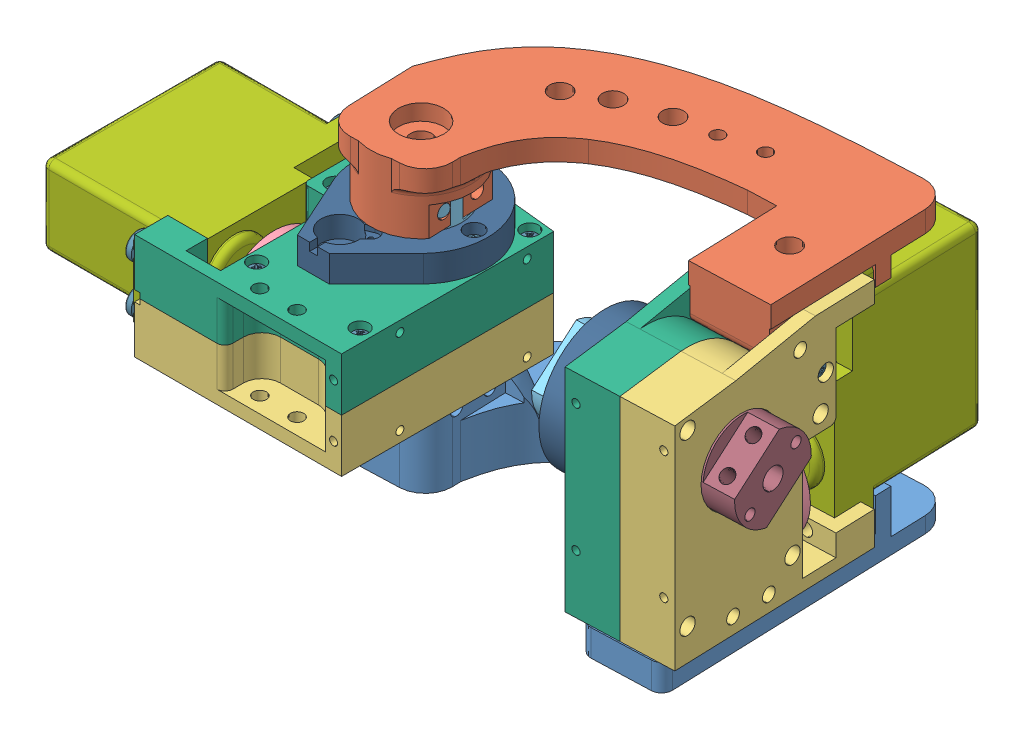
SolidWorks assembly Mirrorshoulder assm, configuration Default. Lengths in mm.
Overall size (244.05 136 145.04).
60 component instances, 14 part files, 11 mates.
Components (placement in the parent):
- bottom bracket-1: bottom bracket [Default] at (151.0032 -30.5 42.744) x (0.999397 0 -0.034735) z (0 1 0) size (146.28 120.67 30)
- top bracket L-1: top bracket L [Default] at (226.2586 75.5 40.1284) x (-0.999397 0 0.034735) z (0 -1 0) size (146.28 120.67 55)
- large gearbox mirror-1: large gearbox mirror [Default] at (-3.3718 24.2748 38.5998) x (0 0 1) z (-1 0 0) size (90.22 74 134.56)
  - bottom housing mirror-1: bottom housing mirror [Default] at (7.4002 -24.2748 -89.7718) x (1 0 0) z (0 -1 0) size (87.5 78 20)
  - wormscrew-1: wormscrew [Default] at (21.4002 -4.2748 -75.7718) x (-0.47589 -0.879505 0) z (0 0 -1) size (40 40 51)
  - driveshaft cog-1: driveshaft cog [Default] at (-6.5998 -9.2748 -103.2718) x (0.623441 0 -0.78187) z (0 1 0) size (49.29 49.31 47)
  - top housing mirror-1: top housing mirror [Default] at (-6.5998 15.7252 -103.2718) x (-1 0 0) z (0 1 0) size (87.5 78 40)
  - HS-805BB-1: HS-805BB [Default] at (2.9002 -19.2748 -28.6693) x (1 0 0) z (0 1 0) size (83 68.8 30)
  - 608ZZ-1: 608ZZ [Default] at (21.4002 -4.2748 -127.5718) x (0.996867 0.079098 0) z (0 0 1) size (22 22 7)
  - 6806 30x42x7-1: 6806 30x42x7 [Default] at (-6.5998 -22.2748 -103.2718) x (0.979879 0 -0.199591) z (0 1 0) size (42 42 7)
  - 6806 30x42x7-2: 6806 30x42x7 [Default] at (-6.5998 9.7252 -103.2718) x (0.968497 0 -0.249026) z (0 -1 0) size (42 42 7)
  - pot holder mirror-1: pot holder mirror [Default] at (-6.5998 15.7252 -103.2718) x (0 0 1) z (0 -1 0) size (50 60 10)
  - cog brace-1: cog brace [Default] at (18.6002 9.7252 -104.6718) x (1 0 0) z (0 -1 0) size (8.5 22.65 3)
  - pot cog-1: pot cog [Default] at (18.6002 12.7252 -97.7718) x (0.51355 0 -0.85806) z (0 -1 0) size (28 27.88 7.9)
  - driveshaft-1: driveshaft [Default] at (-6.5998 -9.2748 -103.2718) x (-0.623441 0 0.78187) z (0 -1 0) size (36.44 35.48 27)
  - Pan Head Cross Recess Screw_ISO-1: Pan Head Cross Recess Screw_ISO [ISO 7045 - M3 x 10 - Z --- 10N] at (-26.5998 23.1252 -103.2718) x (0 -1 0) z (0 0 -1) size (12.35 5.6 5.6)
  - Pan Head Cross Recess Screw_ISO-2: Pan Head Cross Recess Screw_ISO [ISO 7045 - M3 x 10 - Z --- 10N] at (-6.5998 23.1252 -123.2718) x (0 -1 0) z (0.495758 0 -0.868461) size (12.35 5.6 5.6)
  - Pan Head Cross Recess Screw_ISO-3: Pan Head Cross Recess Screw_ISO [ISO 7045 - M3 x 10 - Z --- 10N] at (-6.5998 23.1252 -83.2718) x (0 -1 0) z (0.927545 0 -0.373711) size (12.35 5.6 5.6)
  - Pan Head Cross Recess Screw_ISO-4: Pan Head Cross Recess Screw_ISO [ISO 7045 - M5 x 12 - Z --- 12N] at (-34.5998 -13.2748 -42.0718) x (0 0 -1) z (-1 0 0) size (15.63 9.5 9.5)
  - Pan Head Cross Recess Screw_ISO-5: Pan Head Cross Recess Screw_ISO [ISO 7045 - M5 x 12 - Z --- 12N] at (-34.5998 4.7252 -42.0718) x (0 0 -1) z (-1 0 0) size (15.63 9.5 9.5)
  - Pan Head Cross Recess Screw_ISO-6: Pan Head Cross Recess Screw_ISO [ISO 7045 - M3 x 30 - Z --- 25N] at (-27.0895 14.1252 -123.7718) x (0 -1 0) z (0 0 -1) size (32.35 5.6 5.6)
  - Pan Head Cross Recess Screw_ISO-7: Pan Head Cross Recess Screw_ISO [ISO 7045 - M3 x 30 - Z --- 25N] at (-18.0998 -22.6748 -69.7718) x (0 1 0) z (0 0 -1) size (32.35 5.6 5.6)
  - Pan Head Cross Recess Screw_ISO-8: Pan Head Cross Recess Screw_ISO [ISO 7045 - M3 x 30 - Z --- 25N] at (34.9002 14.1252 -82.7718) x (0 -1 0) z (-0.8218 0 -0.569776) size (32.35 5.6 5.6)
  - Pan Head Cross Recess Screw_ISO-9: Pan Head Cross Recess Screw_ISO [ISO 7045 - M3 x 30 - Z --- 25N] at (-5.5998 14.1252 -71.7718) x (0 -1 0) z (0.38373 0 -0.923445) size (32.35 5.6 5.6)
  - Pan Head Cross Recess Screw_ISO-10: Pan Head Cross Recess Screw_ISO [ISO 7045 - M2 x 6 - Z --- 6N] at (18.6002 6.6252 -115.2718) x (0 1 0) z (0.855583 0 0.517665) size (7.57 4 4)
  - Pan Head Cross Recess Screw_ISO-11: Pan Head Cross Recess Screw_ISO [ISO 7045 - M3 x 5 - Z --- 5N] at (-19.8916 -13.6748 -113.8703) x (0 1 0) z (0.934817 0 -0.355129) size (7.35 5.6 5.6)
  - Pan Head Cross Recess Screw_ISO-12: Pan Head Cross Recess Screw_ISO [ISO 7045 - M3 x 5 - Z --- 5N] at (9.2246 -13.6748 -109.4836) x (0 1 0) z (-0.000145 0 -1) size (7.35 5.6 5.6)
  - Pan Head Cross Recess Screw_ISO-13: Pan Head Cross Recess Screw_ISO [ISO 7045 - M3 x 5 - Z --- 5N] at (-9.1325 -13.6748 -86.4615) x (0 1 0) z (-0.12044 0 -0.992721) size (7.35 5.6 5.6)
  - Pan Head Cross Recess Screw_ISO-14: Pan Head Cross Recess Screw_ISO [ISO 7045 - M3 x 30 - Z --- 25N] at (36.9002 14.1252 -123.7718) x (0 -1 0) z (0.993717 0 0.111922) size (32.35 5.6 5.6)
  - Pan Head Cross Recess Screw_ISO-15: Pan Head Cross Recess Screw_ISO [ISO 7045 - M5 x 12 - Z --- 12N] at (40.4002 4.7252 -42.0718) x (0 0 -1) z (0.445798 -0.895134 0) size (15.63 9.5 9.5)
  - Pan Head Cross Recess Screw_ISO-16: Pan Head Cross Recess Screw_ISO [ISO 7045 - M5 x 12 - Z --- 12N] at (40.4002 -13.2748 -42.0718) x (0 0 -1) z (0.583619 -0.812027 0) size (15.63 9.5 9.5)
- large gearbox mirror-2: large gearbox mirror [Default] at (203.0039 28.9002 -59.652) x (0 -1 0) z (-0.034735 0 -0.999397) size (90.22 74 134.56)
  - bottom housing mirror-1: bottom housing mirror [Default] at (7.4002 -24.2748 -89.7718) x (1 0 0) z (0 -1 0) size (87.5 78 20)
  - wormscrew-1: wormscrew [Default] at (21.4002 -4.2748 -75.7718) x (-0.47589 -0.879505 0) z (0 0 -1) size (40 40 51)
  - driveshaft cog-1: driveshaft cog [Default] at (-6.5998 -9.2748 -103.2718) x (0.623441 0 -0.78187) z (0 1 0) size (49.29 49.31 47)
  - top housing mirror-1: top housing mirror [Default] at (-6.5998 15.7252 -103.2718) x (-1 0 0) z (0 1 0) size (87.5 78 40)
  - HS-805BB-1: HS-805BB [Default] at (2.9002 -19.2748 -28.6693) x (1 0 0) z (0 1 0) size (83 68.8 30)
  - 608ZZ-1: 608ZZ [Default] at (21.4002 -4.2748 -127.5718) x (0.996867 0.079098 0) z (0 0 1) size (22 22 7)
  - 6806 30x42x7-1: 6806 30x42x7 [Default] at (-6.5998 -22.2748 -103.2718) x (0.979879 0 -0.199591) z (0 1 0) size (42 42 7)
  - 6806 30x42x7-2: 6806 30x42x7 [Default] at (-6.5998 9.7252 -103.2718) x (0.968497 0 -0.249026) z (0 -1 0) size (42 42 7)
  - pot holder mirror-1: pot holder mirror [Default] at (-6.5998 15.7252 -103.2718) x (0 0 1) z (0 -1 0) size (50 60 10)
  - cog brace-1: cog brace [Default] at (18.6002 9.7252 -104.6718) x (1 0 0) z (0 -1 0) size (8.5 22.65 3)
  - pot cog-1: pot cog [Default] at (18.6002 12.7252 -97.7718) x (0.51355 0 -0.85806) z (0 -1 0) size (28 27.88 7.9)
  - driveshaft-1: driveshaft [Default] at (-6.5998 -9.2748 -103.2718) x (-0.623441 0 0.78187) z (0 -1 0) size (36.44 35.48 27)
  - Pan Head Cross Recess Screw_ISO-1: Pan Head Cross Recess Screw_ISO [ISO 7045 - M3 x 10 - Z --- 10N] at (-26.5998 23.1252 -103.2718) x (0 -1 0) z (0 0 -1) size (12.35 5.6 5.6)
  - Pan Head Cross Recess Screw_ISO-2: Pan Head Cross Recess Screw_ISO [ISO 7045 - M3 x 10 - Z --- 10N] at (-6.5998 23.1252 -123.2718) x (0 -1 0) z (0.495758 0 -0.868461) size (12.35 5.6 5.6)
  - Pan Head Cross Recess Screw_ISO-3: Pan Head Cross Recess Screw_ISO [ISO 7045 - M3 x 10 - Z --- 10N] at (-6.5998 23.1252 -83.2718) x (0 -1 0) z (0.927545 0 -0.373711) size (12.35 5.6 5.6)
  - Pan Head Cross Recess Screw_ISO-4: Pan Head Cross Recess Screw_ISO [ISO 7045 - M5 x 12 - Z --- 12N] at (-34.5998 -13.2748 -42.0718) x (0 0 -1) z (-1 0 0) size (15.63 9.5 9.5)
  - Pan Head Cross Recess Screw_ISO-5: Pan Head Cross Recess Screw_ISO [ISO 7045 - M5 x 12 - Z --- 12N] at (-34.5998 4.7252 -42.0718) x (0 0 -1) z (-1 0 0) size (15.63 9.5 9.5)
  - Pan Head Cross Recess Screw_ISO-6: Pan Head Cross Recess Screw_ISO [ISO 7045 - M3 x 30 - Z --- 25N] at (-27.0895 14.1252 -123.7718) x (0 -1 0) z (0 0 -1) size (32.35 5.6 5.6)
  - Pan Head Cross Recess Screw_ISO-7: Pan Head Cross Recess Screw_ISO [ISO 7045 - M3 x 30 - Z --- 25N] at (-18.0998 -22.6748 -69.7718) x (0 1 0) z (0 0 -1) size (32.35 5.6 5.6)
  - Pan Head Cross Recess Screw_ISO-8: Pan Head Cross Recess Screw_ISO [ISO 7045 - M3 x 30 - Z --- 25N] at (34.9002 14.1252 -82.7718) x (0 -1 0) z (-0.8218 0 -0.569776) size (32.35 5.6 5.6)
  - Pan Head Cross Recess Screw_ISO-9: Pan Head Cross Recess Screw_ISO [ISO 7045 - M3 x 30 - Z --- 25N] at (-5.5998 14.1252 -71.7718) x (0 -1 0) z (0.38373 0 -0.923445) size (32.35 5.6 5.6)
  - Pan Head Cross Recess Screw_ISO-10: Pan Head Cross Recess Screw_ISO [ISO 7045 - M2 x 6 - Z --- 6N] at (18.6002 6.6252 -115.2718) x (0 1 0) z (0.855583 0 0.517665) size (7.57 4 4)
  - Pan Head Cross Recess Screw_ISO-11: Pan Head Cross Recess Screw_ISO [ISO 7045 - M3 x 5 - Z --- 5N] at (-19.8916 -13.6748 -113.8703) x (0 1 0) z (0.934817 0 -0.355129) size (7.35 5.6 5.6)
  - Pan Head Cross Recess Screw_ISO-12: Pan Head Cross Recess Screw_ISO [ISO 7045 - M3 x 5 - Z --- 5N] at (9.2246 -13.6748 -109.4836) x (0 1 0) z (-0.000145 0 -1) size (7.35 5.6 5.6)
  - Pan Head Cross Recess Screw_ISO-13: Pan Head Cross Recess Screw_ISO [ISO 7045 - M3 x 5 - Z --- 5N] at (-9.1325 -13.6748 -86.4615) x (0 1 0) z (-0.12044 0 -0.992721) size (7.35 5.6 5.6)
  - Pan Head Cross Recess Screw_ISO-14: Pan Head Cross Recess Screw_ISO [ISO 7045 - M3 x 30 - Z --- 25N] at (36.9002 14.1252 -123.7718) x (0 -1 0) z (0.993717 0 0.111922) size (32.35 5.6 5.6)
  - Pan Head Cross Recess Screw_ISO-15: Pan Head Cross Recess Screw_ISO [ISO 7045 - M5 x 12 - Z --- 12N] at (40.4002 4.7252 -42.0718) x (0 0 -1) z (0.445798 -0.895134 0) size (15.63 9.5 9.5)
  - Pan Head Cross Recess Screw_ISO-16: Pan Head Cross Recess Screw_ISO [ISO 7045 - M5 x 12 - Z --- 12N] at (40.4002 -13.2748 -42.0718) x (0 0 -1) z (0.583619 -0.812027 0) size (15.63 9.5 9.5)
Mates (geometry in assembly coordinates):
- Concentric7: concentric anti-aligned: circle of top bracket L-1; circle of large gearbox mirror-1/driveshaft cog-1
- Coincident9: coincident aligned: plane of top bracket L-1 through (99.9 50.5 32) normal (0 -1 0); circle of large gearbox mirror-1/driveshaft cog-1
- Coincident14: coincident anti-aligned: circle of large gearbox mirror-2/bottom housing mirror-1; circle of top bracket L-1
- Coincident15: coincident anti-aligned: plane of top bracket L-1 through (153.4127 67.5 -38.8243) normal (0 -1 0); plane of large gearbox mirror-2/bottom housing mirror-1 through (185.5017 67.5 14.7727) normal (0 1 0)
- Coincident16: coincident anti-aligned: circle of bottom bracket-1; circle of large gearbox mirror-2/bottom housing mirror-1
- Coincident17: coincident anti-aligned: circle of bottom bracket-1; circle of large gearbox mirror-2/bottom housing mirror-1
- Concentric8: concentric aligned: circle of bottom bracket-1; circle of large gearbox mirror-1/driveshaft-1
- Concentric9: concentric anti-aligned: circle of bottom bracket-1; circle of large gearbox mirror-2/bottom housing mirror-1
- Coincident18: coincident anti-aligned: unknown of large gearbox mirror-1/HS-805BB-1
- Coincident19: coincident anti-aligned: unknown of large gearbox mirror-1/bottom housing mirror-1
- Coincident21: coincident anti-aligned: unknown of large gearbox mirror-1/top housing mirror-1
